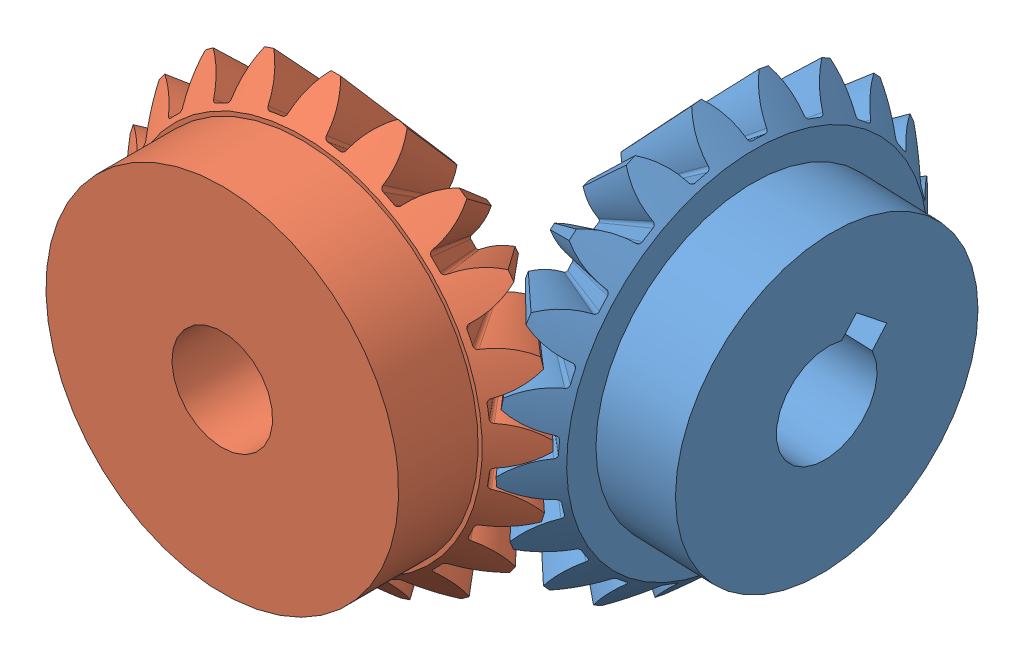
SolidWorks assembly MotionTest, configuration Default. Lengths in mm.
Overall size (55.67 60.71 59.99).
3 component instances, 2 part files, 0 mates.
Components (placement in the parent):
- Pinion Gear System-1: Pinion Gear System [Default] at (405.8083 1414.2601 81.6117) size (55.67 60.71 59.99)
  - straight bevel gear_am-1: straight bevel gear_am [Metric - Straight bevel gear 2M 20GT 20PT 20PA 12FW ---20O30H30MD10S1] at (-367.4444 -1387.6419 -30.0001) x (-0.999245 0.038861 0) z (-0.024303 -0.624899 -0.780327) size (19.85 42.67 42.67)
  - straight bevel pinion_am-1: straight bevel pinion_am [Metric - Straight bevel pinion 2M20PT 20GT 20PA 12FW ---20O35H30MD10N] at (-389.5287 -1386.783 -7.8991) x (0 0 -1) z (0.986616 0.163058 0) size (19.85 42.67 42.67)
